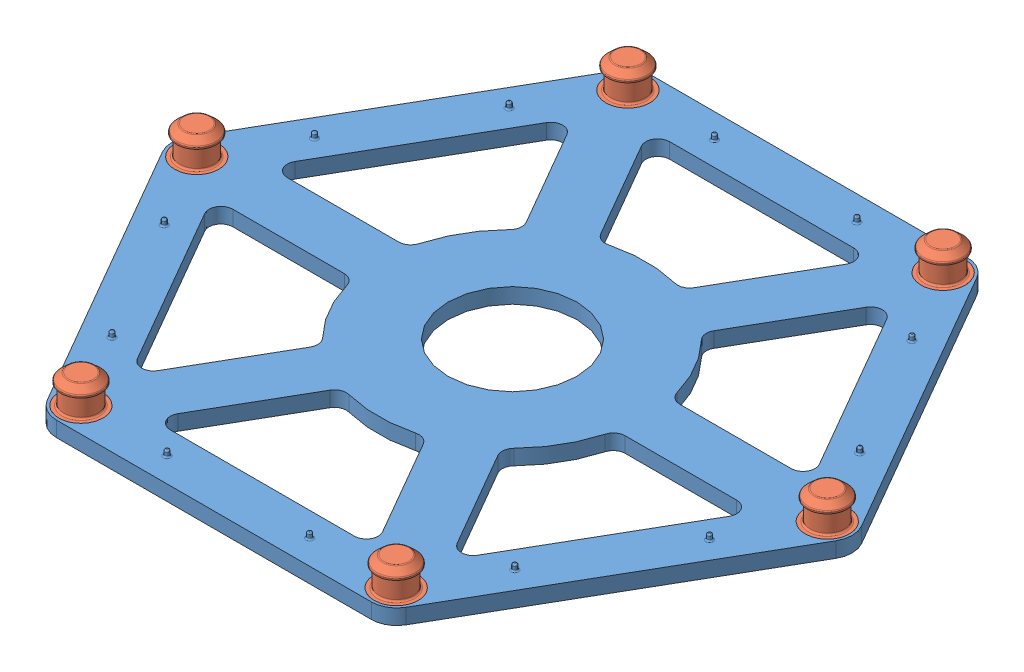
SolidWorks assembly small_floor_joints, configuration Default. Lengths in mm.
Overall size (92.31 5.98 80.87).
7 component instances, 2 part files, 12 mates.
Components (placement in the parent):
- small_floor-1: small_floor [Default] at (32.8758 38.4314 61.817) size (92.31 2.87 80.87)
- swivel_plug-1: swivel_plug [Default] at (-9.9248 38.6385 61.7812) size (5.98 5.98 5.98)
- swivel_plug-2: swivel_plug [Default] at (11.4447 38.6385 98.866) size (5.98 5.98 5.98)
- swivel_plug-3: swivel_plug [Default] at (54.2459 38.6385 98.9019) size (5.98 5.98 5.98)
- swivel_plug-4: swivel_plug [Default] at (75.6775 38.6385 61.8529) size (5.98 5.98 5.98)
- swivel_plug-5: swivel_plug [Default] at (54.308 38.6385 24.768) size (5.98 5.98 5.98)
- swivel_plug-6: swivel_plug [Default] at (11.5068 38.6385 24.7322) size (5.98 5.98 5.98)
Mates (geometry in assembly coordinates):
- Concentric2: concentric aligned: cylinder of small_floor_18H-1 through (-9.9248 40.3664 61.7812) axis (0 -1 0) radius 2.99; cylinder of swivel_plug-1 through (-9.9248 40.3664 61.7812) axis (0 -1 0) radius 2.99
- Coincident1: coincident aligned: plane of small_floor_18H-1 through (32.8763 38.2964 61.817) normal (0 -1 0); plane of swivel_plug-1 through (-9.9248 38.2964 61.7812) normal (0 -1 0)
- Concentric3: concentric aligned: cylinder of small_floor_18H-1 through (11.4447 40.3664 98.866) axis (0 -1 0) radius 2.99; cylinder of swivel_plug-2 through (11.4447 40.3664 98.866) axis (0 -1 0) radius 2.99
- Coincident2: coincident aligned: plane of small_floor_18H-1 through (32.8763 38.2964 61.817) normal (0 -1 0); plane of swivel_plug-2 through (11.4447 38.2964 98.866) normal (0 -1 0)
- Concentric4: concentric aligned: cylinder of small_floor_18H-1 through (54.2459 40.3664 98.9019) axis (0 -1 0) radius 2.99; cylinder of swivel_plug-3 through (54.2459 40.3664 98.9019) axis (0 -1 0) radius 2.99
- Coincident3: coincident aligned: plane of small_floor_18H-1 through (32.8763 38.2964 61.817) normal (0 -1 0); plane of swivel_plug-3 through (54.2459 38.2964 98.9019) normal (0 -1 0)
- Concentric5: concentric aligned: cylinder of small_floor_18H-1 through (75.6775 40.3664 61.8529) axis (0 -1 0) radius 2.99; cylinder of swivel_plug-4 through (75.6775 40.3664 61.8529) axis (0 -1 0) radius 2.99
- Coincident4: coincident aligned: plane of small_floor_18H-1 through (32.8763 38.2964 61.817) normal (0 -1 0); plane of swivel_plug-4 through (75.6775 38.2964 61.8529) normal (0 -1 0)
- Concentric6: concentric aligned: cylinder of small_floor_18H-1 through (54.308 40.3664 24.768) axis (0 -1 0) radius 2.99; cylinder of swivel_plug-5 through (54.308 40.3664 24.768) axis (0 -1 0) radius 2.99
- Coincident5: coincident aligned: plane of small_floor_18H-1 through (32.8763 38.2964 61.817) normal (0 -1 0); plane of swivel_plug-5 through (54.308 38.2964 24.768) normal (0 -1 0)
- Concentric7: concentric aligned: cylinder of small_floor_18H-1 through (11.5068 40.3664 24.7322) axis (0 -1 0) radius 2.99; cylinder of swivel_plug-6 through (11.5068 40.3664 24.7322) axis (0 -1 0) radius 2.99
- Coincident6: coincident aligned: plane of small_floor_18H-1 through (32.8763 38.2964 61.817) normal (0 -1 0); plane of swivel_plug-6 through (11.5068 38.2964 24.7322) normal (0 -1 0)
